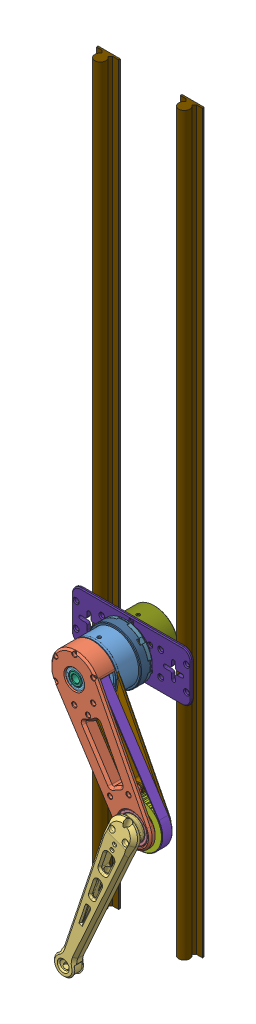
SolidWorks assembly Leg 011, configuration Default. Lengths in mm.
Overall size (161.9 802.2 102.94).
20 component instances, 18 part files, 46 mates.
Components (placement in the parent):
- Servo 010-1: Servo 010 [Default] at (15.0435 28.5731 29.2983) size (52.8 52.8 26)
- Femur 011-1: Femur 011 [Default] at (15.0435 28.5731 74.4483) x (0.866025 0.5 0) z (0 0 1) size (53 172 20.25)
- Low Limb 020-1: Low Limb 020 [Predeterminado] at (77.7935 -80.1131 89.8983) x (-0.931105 0.364752 0) z (0 0 -1) size (30 188.77 21.4)
- 6705 Bearing-1: 6705 Bearing [Predeterminado] at (77.7935 -80.1131 71.4983) x (0.989844 0.142156 0) z (0.142156 -0.989844 0) size (32 4.1 32)
- Bearing 15x24x5mm-1: Bearing 15x24x5mm [Predeterminado] at (15.0435 28.5731 70.6483) x (1 0 0) z (0 -1 0) size (24 5.1 24)
- Pulley A 36T 011-1: Pulley A 36T 011 [Predeterminado] at (15.0435 28.5731 66.0983) x (-1 0 0) z (0 0 -1) size (36.31 36.31 18.05)
- Pulley B 36T 010-2: Pulley B 36T 010 [Predeterminado] at (77.7935 -80.1131 55.8983) x (0.364752 0.931105 0) z (0 0 1) size (49.11 49.11 20.55)
- Belt 380mm 010-1: Belt 380mm 010 [Default] at (77.7935 -80.1131 65.9983) x (-0.5 0.866025 0) z (-0.866025 -0.5 0) size (168.7 10 50)
- Femur B 011-1: Femur B 011 [Default] at (15.0435 28.5731 49.7229) x (-0.866025 -0.5 0) z (0 0 -1) size (52.55 140.48 13)
- 6705 Bearing-2: 6705 Bearing [Predeterminado] at (77.7935 -80.1131 52.4229) x (0.58942 -0.807827 0) z (-0.807827 -0.58942 0) size (32 4.1 32)
- Back Plate 012-1: Back Plate 012 [Default] at (15.0435 28.5731 31.0483) x (1 0 0) z (0 1 0) size (58 10.25 57.37)
- Pulley B Plate 010-1: Pulley B Plate 010 [Default] at (77.7935 -80.1131 48.8983) x (-0.364752 -0.931105 0) z (0 0 -1) size (27 27 7.25)
- Dagor Controller Board 2.5-1: Dagor Controller Board 2.5 [Predeterminado] at (15.0435 28.5731 24.4983) size (44 44 7.5)
- ESP32-WROOM-32U-1: ESP32-WROOM-32U [Default] at (9.0435 43.9731 23.5333) x (1 0 0) z (0 0 -1) size (18.07 19.38 3.04)
- Back Plate B 013-1: Back Plate B 013 [Default] at (15.0435 28.5731 22.7073) x (-1 0 0) z (0 0 -1) size (58 58 9.75)
- Magnet Holder 010-1: Magnet Holder 010 [Default] at (15.0435 28.5731 36.0983) x (1 0 0) z (0 0 -1) size (9 9 8.5)
- Servo (wo front plate) 010-1: Servo (wo front plate) 010 [Default] at (15.0435 28.5731 -13.0427) size (52.8 52.8 26)
- J2 Front Plate 010-1: J2 Front Plate 010 [Default] at (15.0435 28.5731 8.9573) size (130 55 3.5)
- Linear Rail 8000mm-1: Linear Rail 8000mm [Default] at (60.8773 554.6932 0.6981) x (1 0 0) z (0 0 -1) size (24.14 800 15.65)
- Linear Rail 8000mm-2: Linear Rail 8000mm [Default] at (-30.361 554.6932 0.6981) x (1 0 0) z (0 0 -1) size (24.14 800 15.65)
Mates (geometry in assembly coordinates):
- Concentric1: concentric anti-aligned: cylinder of Servo 010-1 through (15.0435 28.5731 54.1983) axis (0 0 -1) radius 26.4; cylinder of Femur 011-1 through (15.0435 28.5731 70.4483) axis (0 0 1) radius 26.5
- Coincident1: coincident anti-aligned: plane of Servo 010-1 through (15.0435 28.5731 54.1983) normal (0 0 1); plane of Femur 011-1 through (15.0435 28.5731 54.1983) normal (0 0 -1)
- Concentric2: concentric aligned: cylinder of Servo 010-1 through (35.6116 40.4481 49.0983) axis (0 0 1) radius 1.25; cylinder of Femur 011-1 through (35.6116 40.4481 70.4483) axis (0 0 1) radius 1.4
- Concentric3: concentric aligned: cylinder of Femur 011-1 through (77.7935 -80.1131 70.4483) axis (0 0 1) radius 14.25; cylinder of Low Limb 020-1 through (77.7935 -80.1131 73.4983) axis (0 0 1) radius 12.5
- Coincident3: coincident anti-aligned: plane of Low Limb 020-1 through (77.7935 -80.1131 73.4983) normal (0 0 -1); plane of 6705 Bearing-1 through (77.7935 -80.1131 73.4983) normal (0 0 1)
- Concentric5: concentric aligned: cylinder of Femur 011-1 through (15.0435 28.5731 73.1983) axis (0 0 -1) radius 12.2; cylinder of Bearing 15x24x5mm-1 through (15.0435 28.5731 73.1483) axis (0 0 -1) radius 12
- Coincident4: coincident anti-aligned: plane of Femur 011-1 through (15.0435 28.5731 73.1983) normal (0 0 -1); plane of Bearing 15x24x5mm-1 through (15.0435 28.5731 73.1983) normal (0 0 1)
- Concentric7: concentric aligned: cylinder of 6705 Bearing-1 through (77.7935 -80.1131 73.4983) axis (0 0 -1) radius 12.5; cylinder of Pulley B 36T 010-2 through (77.7935 -80.1131 72.1983) axis (0 0 -1) radius 12.45
- Concentric8: concentric aligned: cylinder of Bearing 15x24x5mm-1 through (15.0435 28.5731 73.1483) axis (0 0 -1) radius 7.5; cylinder of Pulley A 36T 010-1 through (15.0435 28.5731 73.3483) axis (0 0 -1) radius 7.45
- Coincident7: coincident anti-aligned: plane of Servo 010-1 through (15.0435 28.5731 55.2983) normal (0 0 1); plane of Pulley A 36T 010-1 through (15.0435 28.5731 55.2983) normal (0 0 -1)
- Parallel1: parallel anti-aligned: plane of Low Limb 020-1 through (85.3411 -73.4575 68.4983) normal (0.931105 -0.364752 0); plane of Pulley B 36T 010-2 through (85.4059 -73.4292 63.1983) normal (-0.931105 0.364752 0)
- Concentric9: concentric aligned: cylinder of Pulley A 36T 010-1 through (15.0435 28.5731 55.8983) axis (0 0 1) radius 17.4; cylinder of Belt 380mm 010-1 through (15.0435 28.5731 55.9983) axis (0 0 1) radius 17.2
- Concentric10: concentric anti-aligned: cylinder of Pulley B 36T 010-2 through (77.7935 -80.1131 66.0983) axis (0 0 -1) radius 24; cylinder of Belt 380mm 010-1 through (77.7935 -80.1131 55.9983) axis (0 0 1) radius 24
- Width1: width anti-aligned: plane of Pulley A 36T 011-1 through (15.0435 28.5731 66.0983) normal (0 0 -1); plane of Pulley A 36T 011-1 through (15.0435 28.5731 55.8983) normal (0 0 1); plane of Belt 380mm 010-1 through (77.7935 -80.1131 65.9983) normal (0 0 1); plane of Belt 380mm 010-1 through (77.7935 -80.1131 55.9983) normal (0 0 -1)
- Concentric14: concentric anti-aligned: cylinder of Servo 010-1 through (15.0435 28.5731 54.1983) axis (0 0 -1) radius 26.4; cylinder of Femur B 010-1 through (15.0435 28.5731 43.7229) axis (0 0 1) radius 26.75
- Concentric15: concentric aligned: cylinder of Femur B 010-1 through (77.7935 -80.1131 54.4729) axis (0 0 -1) radius 16.25; cylinder of 6705 Bearing-2 through (77.7935 -80.1131 54.4229) axis (0 0 -1) radius 16
- Coincident10: coincident anti-aligned: plane of Femur B 010-1 through (77.7935 -80.1131 54.4729) normal (0 0 -1); plane of 6705 Bearing-2 through (77.7935 -80.1131 54.4729) normal (0 0 1)
- Concentric16: concentric anti-aligned: cylinder of Pulley B 36T 010-2 through (77.7935 -80.1131 51.6483) axis (0 0 1) radius 12.45; cylinder of 6705 Bearing-2 through (77.7935 -80.1131 54.4229) axis (0 0 -1) radius 12.5
- Concentric17: concentric anti-aligned: cylinder of Femur 011-1 through (77.7935 -80.1131 69.4483) axis (0 0 1) radius 16.25; cylinder of 6705 Bearing-1 through (77.7935 -80.1131 73.4983) axis (0 0 -1) radius 16
- Coincident11: coincident anti-aligned: plane of Femur 011-1 through (77.7935 -80.1131 69.4483) normal (0 0 1); plane of 6705 Bearing-1 through (77.7935 -80.1131 69.4483) normal (0 0 -1)
- Width2: width anti-aligned: plane of Belt 380mm 010-1 through (77.7935 -80.1131 65.9983) normal (0 0 1); plane of Belt 380mm 010-1 through (77.7935 -80.1131 55.9983) normal (0 0 -1); plane of Pulley B 36T 010-2 through (77.7935 -80.1131 66.0983) normal (0 0 -1); plane of Pulley B 36T 010-2 through (77.7935 -80.1131 55.8983) normal (0 0 1)
- Concentric18: concentric anti-aligned: cylinder of Servo 010-1 through (15.0435 28.5731 31.3983) axis (0 0 -1) radius 9; cylinder of Back Plate 010-1 through (15.0435 28.5731 29.2983) axis (0 0 1) radius 8.75
- Concentric19: concentric anti-aligned: cylinder of Servo 010-1 through (9.0435 28.5731 33.5983) axis (0 0 -1) radius 1.25; cylinder of Back Plate 010-1 through (9.0435 28.5731 29.2983) axis (0 0 1) radius 1.25
- Coincident13: coincident anti-aligned: plane of Pulley B 36T 010-2 through (77.7935 -80.1131 51.6483) normal (0 0 -1); plane of Pulley B Plate 010-1 through (77.7935 -80.1131 51.6483) normal (0 0 1)
- Concentric20: concentric aligned: cylinder of 6705 Bearing-2 through (77.7935 -80.1131 54.4229) axis (0 0 -1) radius 12.5; cylinder of Pulley B Plate 010-1 through (77.7935 -80.1131 51.6483) axis (0 0 -1) radius 12.45
- Concentric21: concentric aligned: cylinder of Pulley B 36T 010-2 through (75.1078 -86.9688 56.6483) axis (0 0 -1) radius 1.45; cylinder of Pulley B Plate 010-1 through (75.1078 -86.9688 51.6483) axis (0 0 -1) radius 1.7
- Coincident14: coincident anti-aligned: plane of Back Plate 010-1 through (15.0435 28.5731 25.2983) normal (0 0 -1); plane of Dagor Controller Board 2.5-1 through (2.5345 41.0821 25.2983) normal (0 0 1)
- Coincident15: coincident anti-aligned: plane of Servo 010-1 through (15.0435 28.5731 29.2983) normal (0 0 -1); plane of Back Plate 010-1 through (15.0435 28.5731 29.2983) normal (0 0 1)
- Concentric23: concentric aligned: cylinder of Back Plate 010-1 through (-3.9565 46.0731 22.7983) axis (0 0 1) radius 1.2; cylinder of Dagor Controller Board 2.5-1 through (-3.9565 46.0731 23.6983) axis (0 0 1) radius 1.5
- Concentric24: concentric aligned: cylinder of Back Plate 010-1 through (34.0435 11.0731 22.7983) axis (0 0 1) radius 1.2; cylinder of Dagor Controller Board 2.5-1 through (34.0435 11.0731 23.6983) axis (0 0 1) radius 1.5
- Coincident16: coincident anti-aligned: plane of Dagor Controller Board 2.5-1 through (15.0435 28.5731 23.4983) normal (0 0 -1); plane of ESP32-WROOM-32U-1 through (18.0435 31.2231 23.4983) normal (0 0 1)
- Width3: width aligned: plane of Dagor Controller Board 2.5-1 through (0.0435 50.5731 23.4983) normal (-1 0 0); plane of Dagor Controller Board 2.5-1 through (18.0435 50.5731 23.4983) normal (1 0 0); plane of ESP32-WROOM-32U-1 through (0.0435 49.4731 23.4983) normal (-1 0 0); plane of ESP32-WROOM-32U-1 through (18.0435 56.7231 23.4983) normal (1 0 0)
- Coincident17: coincident aligned: plane of Dagor Controller Board 2.5-1 through (18.0435 31.2231 23.4983) normal (0 -1 0); plane of ESP32-WROOM-32U-1 through (18.0435 31.2231 23.4983) normal (0 -1 0)
- Concentric25: concentric anti-aligned: cylinder of Servo 010-1 through (15.0435 28.5731 54.1983) axis (0 0 -1) radius 26.4; cylinder of Back Plate B 012-1 through (15.0435 28.5731 15.9573) axis (0 0 1) radius 29
- Parallel2: parallel anti-aligned: plane of Back Plate 010-1 through (37.2935 34.0731 20.7983) normal (0 1 0); plane of Back Plate B 012-1 through (37.0441 34.3231 20.2073) normal (0 -1 0)
- Concentric26: concentric anti-aligned: cylinder of Servo 010-1 through (15.0435 28.5731 35.6983) axis (0 0 -1) radius 2.9; cylinder of Magnet Holder 010-1 through (15.0435 28.5731 33.0983) axis (0 0 1) radius 2.95
- Coincident19: coincident anti-aligned: plane of Servo 010-1 through (15.0435 28.5731 33.5983) normal (0 0 -1); plane of Magnet Holder 010-1 through (15.0435 28.5731 33.5983) normal (0 0 1)
- Concentric30: concentric anti-aligned: cylinder of Servo 010-1 through (15.0435 42.0731 48.1983) axis (0 0 1) radius 1.5; cylinder of Pulley A 36T 011-1 through (15.0435 42.0731 73.3483) axis (0 0 -1) radius 1.675
- Concentric32: concentric anti-aligned: cylinder of Back Plate B 012-1 through (15.0435 42.0731 22.7073) axis (0 0 -1) radius 1.7; cylinder of Servo (wo front plate) 010-1 through (15.0435 42.0731 5.8573) axis (0 0 1) radius 1.5
- Concentric33: concentric aligned: cylinder of Servo 010-1 through (15.0435 28.5731 54.1983) axis (0 0 -1) radius 26.4; cylinder of Servo (wo front plate) 010-1 through (15.0435 28.5731 11.8573) axis (0 0 -1) radius 26.4
- Coincident22: coincident anti-aligned: plane of Back Plate B 012-1 through (15.0435 28.5731 12.9573) normal (0 0 -1); plane of Servo (wo front plate) 010-1 through (15.0435 28.5731 12.9573) normal (0 0 1)
- Concentric34: concentric aligned: cylinder of Servo (wo front plate) 010-1 through (15.0435 28.5731 11.0573) axis (0 0 -1) radius 21.95; cylinder of J2 Front Plate 010-1 through (15.0435 28.5731 11.2573) axis (0 0 -1) radius 22.25
- Coincident24: coincident anti-aligned: plane of Servo (wo front plate) 010-1 through (15.0435 28.5731 8.9573) normal (0 0 1); plane of J2 Front Plate 010-1 through (70.0435 46.0731 8.9573) normal (0 0 -1)
- Concentric35: concentric aligned: cylinder of Servo (wo front plate) 010-1 through (35.6116 40.4481 6.7573) axis (0 0 1) radius 1.25; cylinder of J2 Front Plate 010-1 through (35.6116 40.4481 8.9573) axis (0 0 1) radius 1.7
- Coincident25: coincident aligned: plane of Linear Rail 8000mm-1 through (48.807 -245.3068 -8.9569) normal (0 0 -1); plane of Linear Rail 8000mm-2 through (-42.4313 -245.3068 -8.9569) normal (0 0 -1)
- Coincident26: coincident aligned: plane of Linear Rail 8000mm-1 through (60.8773 -245.3068 0.6981) normal (0 -1 0); plane of Linear Rail 8000mm-2 through (-30.361 -245.3068 0.6981) normal (0 -1 0)
